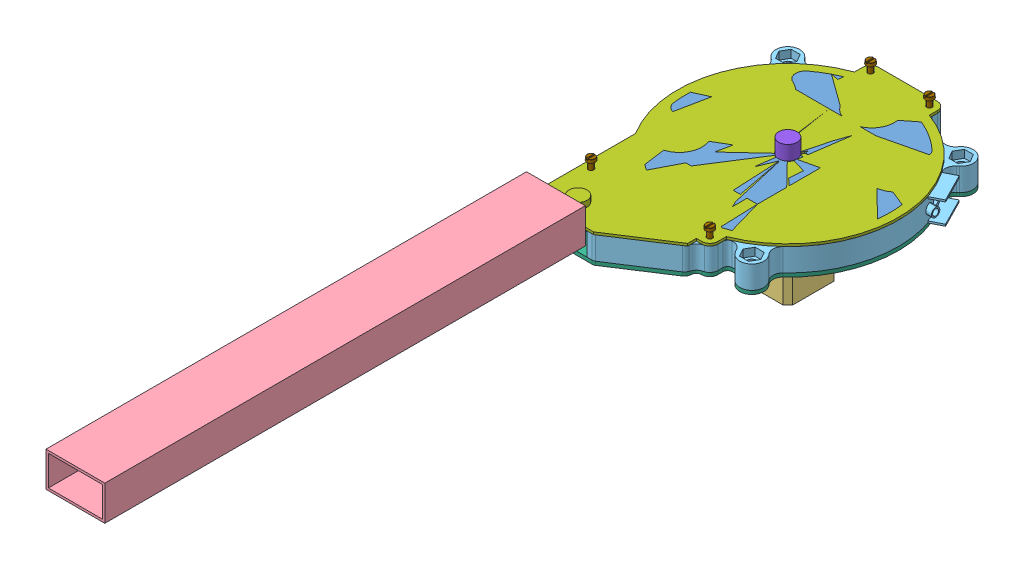
SolidWorks assembly Ensamblaje, configuration Predeterminado. Lengths in mm.
Overall size (226.85 113.82 660.54).
20 component instances, 10 part files, 47 mates.
Components (placement in the parent):
- Prototipo-1: Prototipo [1] x (0.537999 0 -0.842946) z (0.842946 0 0.537999) size (170 17 160.61)
- Tapa Coca Cola amarilla-1: Tapa Coca Cola amarilla [Predeterminado] at (-57.019 -11.5 -35.1829) x (0.748171 0 0.663506) z (-0.663506 0 0.748171) size (30 15 30)
- Motor NEMA 17-1: Motor NEMA 17 [Predeterminado] at (0 -62 0) x (0 0 1) z (-1 0 0) size (42.3 61 42.3)
- Cargador-1: Cargador [Predeterminado] at (-47.4501 17.8243 345.6802) x (-1 0 0) z (0 1 0) size (49 400 29)
- Paredes paletas-1: Paredes paletas [Predeterminado] at origin size (189.03 34 237.43)
  - Curvas paletas-2: Curvas paletas [Predeterminado] at (0 -3 0) size (189.03 19.1 237.43)
  - Tapa atras paletas-3: Tapa atras paletas [Predeterminado] at origin size (184 8.05 237.41)
  - Tapa frente paletas-1: Tapa frente paletas [Predeterminado] at (0 22 0) size (184 7 237.25)
- Acople NEMA 17 v2-1: Acople NEMA 17 v2 [Predeterminado] at (0 -27.5 0) x (1 0 0) z (0 -1 0) size (32 29.93 53.5)
- slotted cheese head screw_din-11: slotted cheese head screw_din [DIN EN ISO 1207 - M4 x 30 - 30N] at (24.5 17.1 -93.3381) x (0 -1 0) z (0 0 1) size (32.61 7 7)
- slotted cheese head screw_din-12: slotted cheese head screw_din [DIN EN ISO 1207 - M4 x 30 - 30N] at (-24.5 17.1 -93.3381) x (0 -1 0) z (0 0 1) size (32.61 7 7)
- slotted cheese head screw_din-13: slotted cheese head screw_din [DIN EN ISO 1207 - M4 x 30 - 30N] at (27.5 17.1 92.4986) x (0 -1 0) z (0 0 1) size (32.61 7 7)
- slotted cheese head screw_din-14: slotted cheese head screw_din [DIN EN ISO 1207 - M4 x 30 - 30N] at (-71.3166 17.1 92.4986) x (0 -1 0) z (0 0 1) size (32.61 7 7)
- hex thin nut gradeb_din-7: hex thin nut gradeb_din [Hexagon Nut ISO 4036 - M4 - N] at (24.5 -12.2 -93.3381) x (0.866025 0 -0.5) z (0 1 0) size (7 8.08 2.2)
- hex thin nut gradeb_din-8: hex thin nut gradeb_din [Hexagon Nut ISO 4036 - M4 - N] at (-24.5 -12.2 -93.3381) x (0.866025 0 -0.5) z (0 1 0) size (7 8.08 2.2)
- hex thin nut gradeb_din-9: hex thin nut gradeb_din [Hexagon Nut ISO 4036 - M4 - N] at (-71.3166 -12.2 92.4986) x (0.866025 0 -0.5) z (0 1 0) size (7 8.08 2.2)
- hex thin nut gradeb_din-10: hex thin nut gradeb_din [Hexagon Nut ISO 4036 - M4 - N] at (27.5 -12.2 92.4986) x (0.866025 0 0.5) z (0 1 0) size (7 8.08 2.2)
- hex thin nut gradeb_din-11: hex thin nut gradeb_din [Hexagon Nut ISO 4036 - M4 - N] at (0 -22.7 73.1645) x (0.866025 0 0.5) z (0 -1 0) size (7 8.08 2.2)
- hex thin nut gradeb_din-12: hex thin nut gradeb_din [Hexagon Nut ISO 4036 - M4 - N] at (-13.15 -22.7 30.15) x (0.866025 0 -0.5) z (0 -1 0) size (7 8.08 2.2)
- hex thin nut gradeb_din-13: hex thin nut gradeb_din [Hexagon Nut ISO 4036 - M4 - N] at (13.15 -22.7 30.15) x (0.866025 0 -0.5) z (0 -1 0) size (7 8.08 2.2)
Mates (geometry in assembly coordinates):
- Coincidente50: coincident aligned: plane of Paredes paletas-1/Tapa atras paletas-3 through (0 0 0) normal (0 0 1); plane of assembly through (0 0 0) normal (0 0 1)
- Coincidente51: coincident aligned: plane of Paredes paletas-1/Tapa atras paletas-3 through (0 0 0) normal (0 1 0); plane of assembly through (0 0 0) normal (0 1 0)
- Coincidente52: coincident aligned: plane of Paredes paletas-1/Tapa atras paletas-3 through (0 0 0) normal (1 0 0); plane of assembly through (0 0 0) normal (1 0 0)
- Coincidente60: coincident: point of Prototipo-1; point of assembly
- Coincidente61: coincident aligned: plane of Prototipo-1 through (0 0 0) normal (0 1 0); plane of assembly through (0 0 0) normal (0 1 0)
- Paralelo21: parallel aligned: plane of Motor NEMA 17-1 through (0 -62 0) normal (0 1 0); plane of assembly through (0 0 0) normal (0 1 0)
- Paralelo22: parallel anti-aligned: plane of Motor NEMA 17-1 through (0 -81.5 0) normal (0 -1 0); plane of Paredes paletas-1/Curvas paletas-2 through (23.15 -83.5 -21.15) normal (0 1 0)
- Coincidente66: coincident anti-aligned: plane of Motor NEMA 17-1 through (0 -8.544 0) normal (0 1 0); plane of ? through (2 -8.544 0) normal (0 -1 0)
- Paralelo23: parallel anti-aligned: plane of ? through (0 -15.544 0) normal (0 -1 0); plane of assembly through (0 0 0) normal (0 1 0)
- Paralelo24: parallel anti-aligned: plane of ? through (0 -15.544 0) normal (0 -1 0); plane of assembly through (0 0 0) normal (0 1 0)
- Coincidente71: coincident anti-aligned: plane of ? through (0 -15.544 0) normal (-1 0 0); plane of assembly through (0 0 0) normal (1 0 0)
- Coincidente72: coincident anti-aligned: plane of ? through (0 -15.544 0) normal (0 0 -1); plane of assembly through (0 0 0) normal (0 0 1)
- Coincidente73: coincident aligned: plane of Acople NEMA 17 v2-1 through (0 -27.5 0) normal (1 0 0); plane of assembly through (0 0 0) normal (1 0 0)
- Paralelo25: parallel anti-aligned: plane of Acople NEMA 17 v2-1 through (0 -27.5 0) normal (0 -1 0); plane of assembly through (0 0 0) normal (0 1 0)
- Coincidente75: coincident anti-aligned: plane of Motor NEMA 17-1 through (0 -20.5 0) normal (0 1 0); plane of Acople NEMA 17 v2-1 through (0 -20.5 0) normal (0 -1 0)
- Coincidente76: coincident aligned: plane of Paredes paletas-1/Tapa atras paletas-3 through (0 0 0) normal (0 0 1); plane of Acople NEMA 17 v2-1 through (0 -27.5 0) normal (0 0 1)
- Distancia1: distance = 2 mm anti-aligned: plane of Motor NEMA 17-1 through (0 -81.5 0) normal (0 -1 0); plane of Paredes paletas-1/Curvas paletas-2 through (23.15 -83.5 -21.15) normal (0 1 0)
- Paralelo26: parallel aligned: plane of Motor NEMA 17-1 through (-21.15 -42.5 -21.15) normal (-1 0 0); plane of Paredes paletas-1/Curvas paletas-2 through (21.15 -124.1634 -19.5134) normal (-1 0 0)
- Coincidente77: coincident anti-aligned: plane of Motor NEMA 17-1 through (21.15 -42.5 21.15) normal (0 0 1); plane of Paredes paletas-1/Curvas paletas-2 through (-23.15 -85.5 21.15) normal (0 0 -1)
- Coincidente78: coincident anti-aligned: plane of Motor NEMA 17-1 through (-21.15 -42.5 -21.15) normal (-1 0 0); plane of Paredes paletas-1/Curvas paletas-2 through (-21.15 -124.1634 -19.5134) normal (1 0 0)
- Concéntrica1: concentric aligned: cylinder of Paredes paletas-1/Tapa atras paletas-3 through (-71.3166 -18.8 92.4986) axis (0 1 0) radius 2; cylinder of ? through (-71.3166 37.5 92.4986) axis (0 1 0) radius 2
- Coincidente83: coincident anti-aligned: plane of Paredes paletas-1/Tapa atras paletas-3 through (0 -12.2 0) normal (0 -1 0); plane of ? through (-77.3788 -12.2 88.9986) normal (0 1 0)
- Concéntrica3: concentric aligned: cylinder of ? through (-71.3166 37.5 92.4986) axis (0 1 0) radius 2; circle of ?
- Coincidente88: coincident anti-aligned: plane of Paredes paletas-1/Tapa atras paletas-3 through (0 -12.2 0) normal (0 -1 0); plane of ? through (-30.5034 -12.2 -96.9379) normal (0 1 0)
- Concéntrica7: concentric aligned: cylinder of Paredes paletas-1/Tapa atras paletas-3 through (-24.5 -32.9693 -93.3381) axis (0 1 0) radius 2; cylinder of ? through (-24.5 -14.4 -93.3381) axis (0 1 0) radius 1.65
- Concéntrica13: concentric aligned: cylinder of slotted cheese head screw_din-11 through (24.5 42.5 -93.3381) axis (0 1 0) radius 2; cylinder of hex thin nut gradeb_din-7 through (24.5 -37.2375 -93.3381) axis (0 1 0) radius 2
- Concéntrica14: concentric aligned: cylinder of slotted cheese head screw_din-12 through (-24.5 42.5 -93.3381) axis (0 1 0) radius 2; cylinder of hex thin nut gradeb_din-8 through (-24.5 -37.2375 -93.3381) axis (0 1 0) radius 2
- Concéntrica15: concentric aligned: cylinder of slotted cheese head screw_din-14 through (-71.3166 42.5 92.4986) axis (0 1 0) radius 2; cylinder of hex thin nut gradeb_din-9 through (-71.3166 -37.2375 92.4986) axis (0 1 0) radius 2
- Concéntrica16: concentric aligned: cylinder of slotted cheese head screw_din-13 through (27.5 42.5 92.4986) axis (0 1 0) radius 2; cylinder of hex thin nut gradeb_din-10 through (27.5 -37.2375 92.4986) axis (0 1 0) radius 2
- Concéntrica17: concentric anti-aligned: cylinder of Paredes paletas-1/Curvas paletas-2 through (0 -85.5 73.1645) axis (0 1 0) radius 2; cylinder of hex thin nut gradeb_din-11 through (0 2.3375 73.1645) axis (0 -1 0) radius 2
- Coincidente94: coincident anti-aligned: plane of Paredes paletas-1/Curvas paletas-2 through (0 -20.5 0) normal (0 -1 0); plane of hex thin nut gradeb_din-11 through (-6.0622 -20.5 69.6645) normal (0 1 0)
- Concéntrica18: concentric anti-aligned: cylinder of Paredes paletas-1/Tapa atras paletas-3 through (-13.15 -18.5 30.15) axis (0 1 0) radius 2; cylinder of hex thin nut gradeb_din-12 through (-13.15 2.3375 30.15) axis (0 -1 0) radius 2
- Concéntrica19: concentric anti-aligned: cylinder of Paredes paletas-1/Curvas paletas-2 through (13.15 -85.5 30.15) axis (0 1 0) radius 2; cylinder of hex thin nut gradeb_din-13 through (13.15 2.3375 30.15) axis (0 -1 0) radius 2
- Coincidente96: coincident anti-aligned: plane of Paredes paletas-1/Curvas paletas-2 through (0 -20.5 0) normal (0 -1 0); plane of hex thin nut gradeb_din-13 through (7.0878 -20.5 33.65) normal (0 1 0)
- Coincidente97: coincident anti-aligned: plane of Paredes paletas-1/Tapa atras paletas-3 through (0 -12.2 0) normal (0 -1 0); plane of hex thin nut gradeb_din-9 through (-77.3788 -12.2 95.9986) normal (0 1 0)
- Paralelo30: parallel anti-aligned: line of Paredes paletas-1/Tapa atras paletas-3 through (-67.2751 -15.5 92.4986) axis (-0.5 0 0.866025); line of hex thin nut gradeb_din-9 through (-69.2959 -14.4 95.9986) axis (0.5 0 -0.866025)
- Coincidente100: coincident: line of Paredes paletas-1/Tapa atras paletas-3 through (31.5415 -12.2 92.4986) axis (-0.5 0 0.866025); plane of hex thin nut gradeb_din-10 through (21.4378 -12.2 88.9986) normal (0 1 0)
- Paralelo31: parallel aligned: line of Paredes paletas-1/Tapa atras paletas-3 through (31.5415 -12.2 92.4986) axis (-0.5 0 0.866025); line of hex thin nut gradeb_din-10 through (31.5415 -12.2 92.4986) axis (-0.5 0 0.866025)
- Coincidente105: coincident anti-aligned: line of Paredes paletas-1/Tapa atras paletas-3 through (-28.5415 -12.2 -93.3381) axis (0.5 0 -0.866025); line of hex thin nut gradeb_din-8 through (-26.5207 -12.2 -96.8381) axis (-0.5 0 0.866025)
- Paralelo34: parallel anti-aligned: line of Paredes paletas-1/Tapa atras paletas-3 through (26.5207 -15.5 -89.8381) axis (-1 0 0); line of hex thin nut gradeb_din-7 through (22.4793 -14.4 -89.8381) axis (1 0 0)
- Coincidente107: coincident anti-aligned: line of Paredes paletas-1/Tapa atras paletas-3 through (26.5207 -12.2 -89.8381) axis (-1 0 0); line of hex thin nut gradeb_din-7 through (22.4793 -12.2 -89.8381) axis (1 0 0)
- Coincidente109: coincident anti-aligned: plane of Paredes paletas-1/Curvas paletas-2 through (0 -20.5 0) normal (0 -1 0); plane of hex thin nut gradeb_din-13 through (7.0878 -20.5 33.65) normal (0 1 0)
- Paralelo36: parallel aligned: line of Paredes paletas-1/Curvas paletas-2 through (15.1707 -23.8 33.65) axis (-1 0 0); line of hex thin nut gradeb_din-13 through (15.1707 -22.7 33.65) axis (-1 0 0)
- Coincidente112: coincident anti-aligned: plane of Paredes paletas-1/Curvas paletas-2 through (0 -20.5 0) normal (0 -1 0); plane of hex thin nut gradeb_din-12 through (-19.2122 -20.5 33.65) normal (0 1 0)
- Paralelo38: parallel anti-aligned: line of Paredes paletas-1/Curvas paletas-2 through (-15.1707 -23.8 33.65) axis (1 0 0); line of hex thin nut gradeb_din-12 through (-11.1293 -22.7 33.65) axis (-1 0 0)
- Coincidente113: coincident anti-aligned: plane of Paredes paletas-1/Curvas paletas-2 through (0 -20.5 0) normal (0 -1 0); plane of hex thin nut gradeb_din-11 through (-6.0622 -20.5 69.6645) normal (0 1 0)
- Coincidente114: coincident aligned: line of Paredes paletas-1/Curvas paletas-2 through (-2.0207 -20.5 76.6645) axis (-0.5 0 -0.866025); line of hex thin nut gradeb_din-11 through (-2.0207 -20.5 76.6645) axis (-0.5 0 -0.866025)
